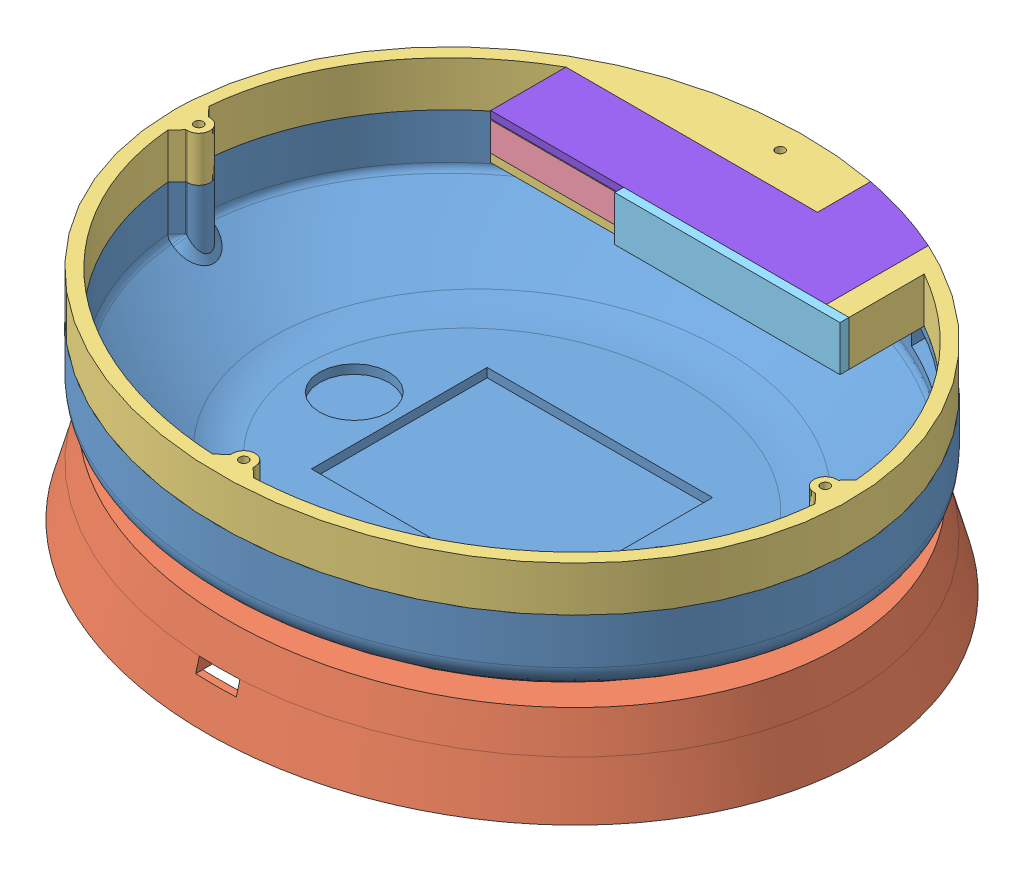
SolidWorks assembly Full_assemble, configuration Default. Lengths in mm.
Overall size (161.23 50.47 140.25).
14 component instances, 11 part files, 11 mates.
Components (placement in the parent):
- Case-UFO_up-1: Case-UFO_up [Default] at origin size (161.23 46.73 140.07) (hidden)
- Case-UFO_down-2: Case-UFO_down [Default] at (0 0.2576 0) size (161.23 42.22 140.15)
- Base_assemble-1: Base_assemble [Default] at (0 0.2576 0) size (159.78 36.93 139.46)
  - Base_up-2: Base_up [Default] at origin size (159.78 36.93 139.46)
  - Base_down-3: Base_down [Default] at (0 -25.3826 0) size (158.24 2.6 138) (hidden)
- Assem-P11-1: Assem-P11 [Default] at (-44.0109 -54.8853 -126.497) size (150.55 10 130.24)
  - Case-UFO_MID-P11-1: Case-UFO_MID-P11 [Default] at (44.0109 65.0828 126.497) size (150.55 10 130.24)
  - P11-1: P11 [Default] at (78.7827 69.4106 91.497) size (74.5 6.4 18.7)
  - hOLDER-p11-1: hOLDER-p11 [Default] at (4.2827 76.0106 91.497) size (74.5 1.6 28.49) (hidden)
  - Fix-P11-1: Fix-P11 [Default] at (83.7827 77.6106 91.497) x (1 0 0) z (0 -1 0) size (50 2 10)
  - Cap-P11-1: Cap-P11 [Default] at (69.4327 72.6106 72.797) x (1 0 0) z (0 1 0) size (18.7 11.79 6.4)
  - Pins-P11-1: Pins-P11 [Default] at (66.1827 73.8606 87.297) x (1 0 0) z (0 1 0) size (9.5 22.15 2)
  - hOLDER-p11-2: hOLDER-p11 [Default] at (4.2827 76.0106 91.497) size (74.5 1.6 28.49)
- Belt-1: Belt [Default] at (-15.3676 31.4844 -37.2458) x (0.021197 0.000774 0.999775) z (-0.984591 -0.173606 0.021009) size (70.59 8.8 10.03) (hidden)
Mates (geometry in assembly coordinates):
- Coincident2: coincident aligned: plane of Case-UFO_up-1 through (0 0 0) normal (1 0 0); plane of Case-UFO_down-2 through (0 0.2576 0) normal (1 0 0)
- Coincident3: coincident aligned: plane of Case-UFO_up-1 through (0 0 0) normal (0 0 1); plane of Case-UFO_down-2 through (0 0.2576 0) normal (0 0 1)
- Coincident4: coincident: line of Base_assemble-1/Base_down-3 through (0 -22.525 -64.2782) axis (0 0 1)
- Coincident5: coincident: line of Base_assemble-1/Base_down-3 through (-74.316 -22.525 0) axis (1 0 0)
- Coincident6: coincident anti-aligned: plane of Case-UFO_down-2 through (-50 -14.525 67.1495) normal (0 -1 0); plane of Base_assemble-1/Base_up-2 through (-50 -14.525 67.1495) normal (0 1 0)
- Concentric1: concentric aligned: cylinder of Case-UFO_down-2 through (69.5 -24.7434 0) axis (0 1 0) radius 1; cylinder of Assem-P11-1/Case-UFO_MID-P11-1 through (69.5 -14.8034 0) axis (0 1 0) radius 1
- Concentric2: concentric aligned: cylinder of Case-UFO_down-2 through (-69.5 -24.7434 0) axis (0 1 0) radius 1; cylinder of Assem-P11-1/Case-UFO_MID-P11-1 through (-69.5 -14.8034 0) axis (0 1 0) radius 1
- Coincident8: coincident anti-aligned: plane of Case-UFO_down-2 through (-75 12.7253 -70.6083) normal (0 1 0); plane of Assem-P11-1/Case-UFO_MID-P11-1 through (-75 12.7253 -70.6083) normal (0 -1 0)
- Distance1: distance = 0.5 mm anti-aligned: plane of Belt-1 through (-15.3908 31.6722 -36.783) normal (0.984591 0.173606 -0.021009); plane of Case-UFO_up-1 through (-8.2533 -1.4552 0.1761) normal (-0.984591 -0.173606 0.021009)
- Distance3: distance = 0.5 mm: point of assembly; point of Belt-1; point of Case-UFO_up-1
- Distance5: distance = 0.5 mm: point of Belt-1; point of Case-UFO_up-1
